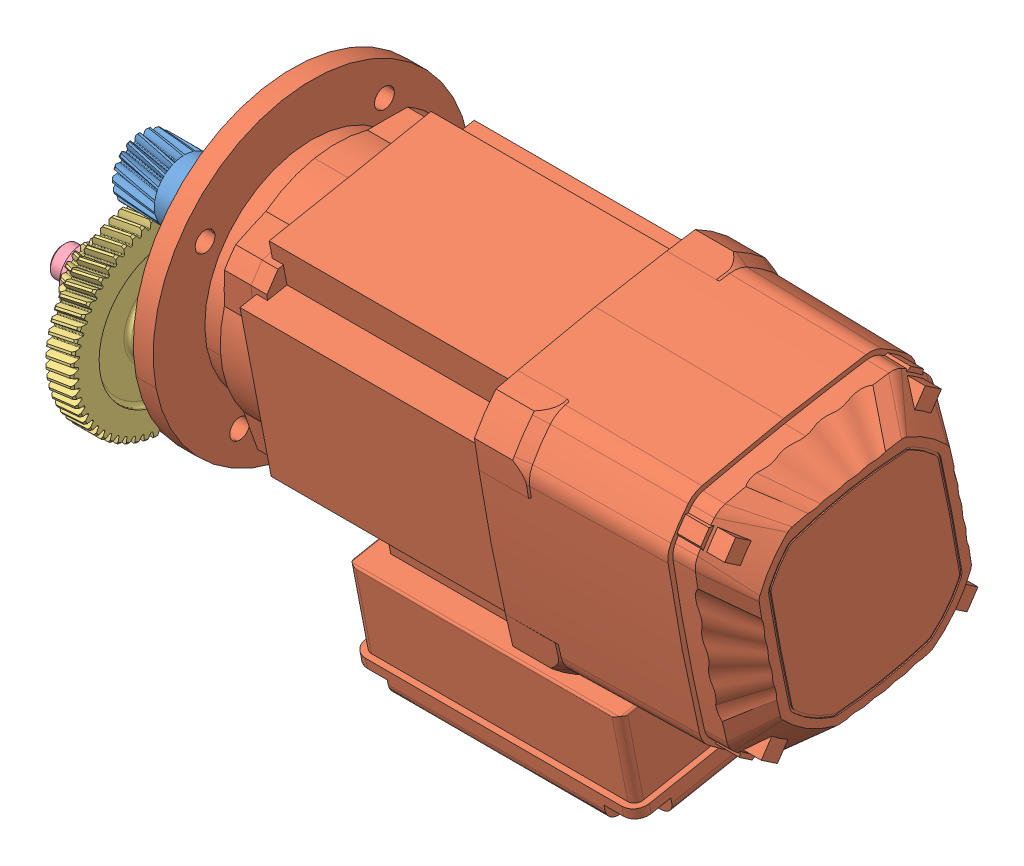
SolidWorks assembly Assem2, configuration Default. Lengths in mm.
Overall size (403.67 235.51 196.67).
8 component instances, 5 part files, 11 mates.
Components (placement in the parent):
- first pinion edit-1: first pinion edit [Default] at (-17.9686 3.1081 2.3259) x (1 0 0) z (0 0.599141 -0.800644) size (40 30.45 30.45)
- DRN71M4_BE05_FF_20230801_100004_YfHfVFymOUmYqMBUzqEm2Q.stp-1: DRN71M4_BE05_FF_20230801_100004_YfHfVFymOUmYqMBUzqEm2Q.stp [Default] at (36.1513 0 0) x (1 0 0) z (0 -0.189285 0.981922) size (318.52 209 160)
- first gear-1: first gear [Default] at (4.1252 -57.1698 -9.6221) x (1 0 0) z (0 -0.361456 0.932389) size (22.52 97.46 97.46)
  - helical gear_3_am-1: helical gear_3_am [Metric - LH Helical gear 1.5M 62T 10HA 20PA 14FW ---62N75H50L18.0N] at (-44.1252 0 10.3198) size (14 97.46 97.46)
- second pinion-1: second pinion [Default] at (-95.0817 -60.0847 5.0965) x (1 0 0) z (0 0.987445 -0.157966) size (65 41.93 41.93)
  - helical gear_3_am-1: helical gear_3_am [second pinion] at (28.0817 5.1613 0) x (1 0 0) z (0 0.849872 -0.52699) size (19 30.45 30.45)
  - Part1^second pinion-1: Part1^second pinion [Default] at origin (virtual)
  - second pinion shaft-1: second pinion shaft [Default] at (16.0817 5.1613 0) x (0 1 0) z (0 0 1) size (22 65 22)
Mates (geometry in assembly coordinates):
- Coincident2: coincident: line of first pinion edit-1 through (0 0 0) axis (-1 0 0)
- Coincident3: coincident: line of first pinion edit-1 through (0 0 0) axis (-1 0 0)
- Coincident5: coincident: line of first pinion edit-1 through (-18 0 0) axis (-1 0 0)
- Coincident7: coincident aligned: plane of first pinion edit-1 through (0 0 0) normal (1 0 0)
- Coincident8: coincident anti-aligned: line of first pinion edit-1 through (-18 0 0) axis (-1 0 0); line of DRN71M4_BE05_FF_20230801_100004_YfHfVFymOUmYqMBUzqEm2Q.stp-1 through (0 29 7.1513) axis (0 0 1)
- Coincident10: coincident aligned: plane of first pinion edit-1 through (-40 0 0) normal (-1 0 0); plane of first gear-1/helical gear_3_am-1 through (-40 -60.9 0) normal (-1 0 0)
- Distance2: distance = 60.9 mm: line of first pinion edit-1 through (-18 0 0) axis (-1 0 0); line of first gear-1 through (-42.348 -60.9 0) axis (1 0 0)
- Coincident13: coincident: line of first gear-1 through (-42.348 -60.9 0) axis (1 0 0)
- GearMate2: gear = 62 : 18 mm: cylinder of first pinion edit-1 through (22.5 0 0) axis (-1 0 0) radius 7; cylinder of first gear-1/helical gear_3_am-1 through (22.5 -60.9 0) axis (-1 0 0) radius 9
- Coincident14: coincident aligned: line of first gear-1 through (-42.348 -60.9 0) axis (1 0 0); line of second pinion-1 through (65 -79 -60.9) axis (0 1 0)
- Coincident19: coincident anti-aligned: plane of first gear-1/helical gear_3_am-1 through (-40 -60.9 0) normal (-1 0 0); plane of second pinion-1/second pinion shaft-1 through (-40 -62.6376 -10.8619) normal (1 0 0)
